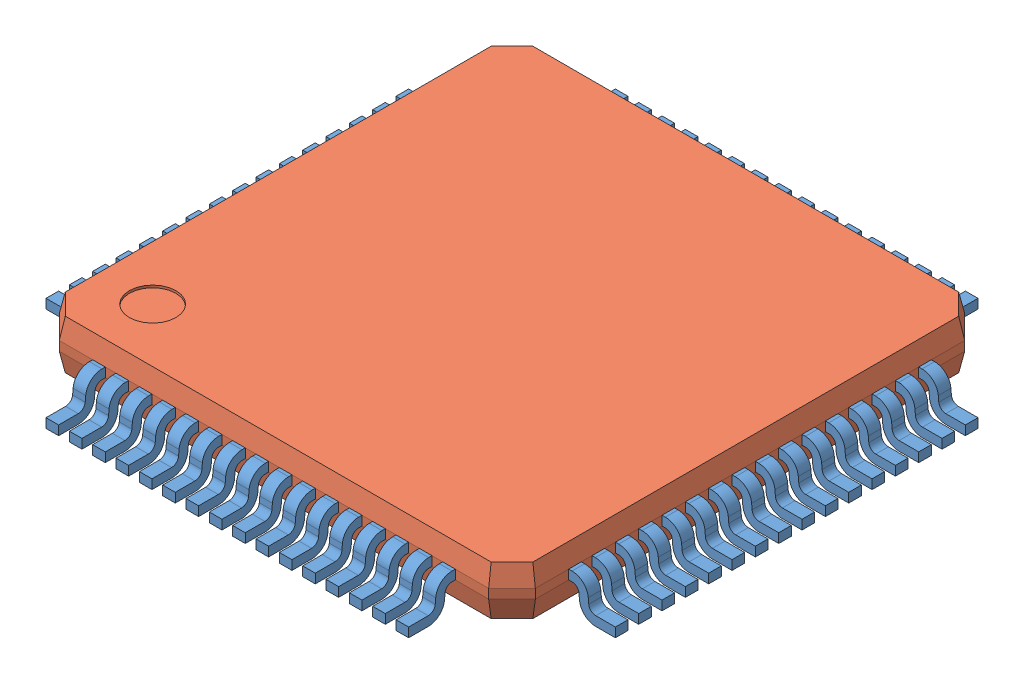
SolidWorks assembly User Library-TQFP64-2, configuration Default. Lengths in mm.
Overall size (12.2 1.2 12.2).
65 component instances, 2 part files, 0 mates.
Components (placement in the parent):
- User Library-TQFP64-2_Leg x0-27 y0-575 z1-0-1: User Library-TQFP64-2_Leg x0-27 y0-575 z1-0 [Default] at (-5.1 0 -1.25) x (0 0 1) z (-1 0 0) size (0.27 0.78 1)
- User Library-TQFP64-2_Leg x0-27 y0-575 z1-0-2: User Library-TQFP64-2_Leg x0-27 y0-575 z1-0 [Default] at (-2.75 0 -5.1001) x (-1 0 0) z (0 0 -1) size (0.27 0.78 1)
- User Library-TQFP64-2_Leg x0-27 y0-575 z1-0-3: User Library-TQFP64-2_Leg x0-27 y0-575 z1-0 [Default] at (-5.1 0 2.25) x (0 0 1) z (-1 0 0) size (0.27 0.78 1)
- User Library-TQFP64-2_Leg x0-27 y0-575 z1-0-4: User Library-TQFP64-2_Leg x0-27 y0-575 z1-0 [Default] at (5.1 0 -3.25) x (0 0 -1) z (1 0 0) size (0.27 0.78 1)
- User Library-TQFP64-2_Leg x0-27 y0-575 z1-0-5: User Library-TQFP64-2_Leg x0-27 y0-575 z1-0 [Default] at (-1.25 0 5.1001) size (0.27 0.78 1)
- User Library-TQFP64-2_Leg x0-27 y0-575 z1-0-6: User Library-TQFP64-2_Leg x0-27 y0-575 z1-0 [Default] at (2.75 0 5.1001) size (0.27 0.78 1)
- User Library-TQFP64-2_Leg x0-27 y0-575 z1-0-7: User Library-TQFP64-2_Leg x0-27 y0-575 z1-0 [Default] at (2.25 0 5.1001) size (0.27 0.78 1)
- User Library-TQFP64-2_Leg x0-27 y0-575 z1-0-8: User Library-TQFP64-2_Leg x0-27 y0-575 z1-0 [Default] at (5.1 0 -0.25) x (0 0 -1) z (1 0 0) size (0.27 0.78 1)
- User Library-TQFP64-2_Leg x0-27 y0-575 z1-0-9: User Library-TQFP64-2_Leg x0-27 y0-575 z1-0 [Default] at (-5.1 0 -0.75) x (0 0 1) z (-1 0 0) size (0.27 0.78 1)
- User Library-TQFP64-2_Leg x0-27 y0-575 z1-0-10: User Library-TQFP64-2_Leg x0-27 y0-575 z1-0 [Default] at (2.25 0 -5.1001) x (-1 0 0) z (0 0 -1) size (0.27 0.78 1)
- User Library-TQFP64-2_Leg x0-27 y0-575 z1-0-11: User Library-TQFP64-2_Leg x0-27 y0-575 z1-0 [Default] at (5.1 0 0.75) x (0 0 -1) z (1 0 0) size (0.27 0.78 1)
- User Library-TQFP64-2_Leg x0-27 y0-575 z1-0-12: User Library-TQFP64-2_Leg x0-27 y0-575 z1-0 [Default] at (-0.25 0 -5.1001) x (-1 0 0) z (0 0 -1) size (0.27 0.78 1)
- User Library-TQFP64-2_Leg x0-27 y0-575 z1-0-13: User Library-TQFP64-2_Leg x0-27 y0-575 z1-0 [Default] at (5.1 0 0.25) x (0 0 -1) z (1 0 0) size (0.27 0.78 1)
- User Library-TQFP64-2_Leg x0-27 y0-575 z1-0-14: User Library-TQFP64-2_Leg x0-27 y0-575 z1-0 [Default] at (1.75 0 5.1001) size (0.27 0.78 1)
- User Library-TQFP64-2_Leg x0-27 y0-575 z1-0-15: User Library-TQFP64-2_Leg x0-27 y0-575 z1-0 [Default] at (-1.25 0 -5.1001) x (-1 0 0) z (0 0 -1) size (0.27 0.78 1)
- User Library-TQFP64-2_Leg x0-27 y0-575 z1-0-16: User Library-TQFP64-2_Leg x0-27 y0-575 z1-0 [Default] at (-5.1 0 1.75) x (0 0 1) z (-1 0 0) size (0.27 0.78 1)
- User Library-TQFP64-2_Leg x0-27 y0-575 z1-0-17: User Library-TQFP64-2_Leg x0-27 y0-575 z1-0 [Default] at (3.25 0 5.1001) size (0.27 0.78 1)
- User Library-TQFP64-2_Leg x0-27 y0-575 z1-0-18: User Library-TQFP64-2_Leg x0-27 y0-575 z1-0 [Default] at (2.75 0 -5.1001) x (-1 0 0) z (0 0 -1) size (0.27 0.78 1)
- User Library-TQFP64-2_Leg x0-27 y0-575 z1-0-19: User Library-TQFP64-2_Leg x0-27 y0-575 z1-0 [Default] at (5.1 0 2.25) x (0 0 -1) z (1 0 0) size (0.27 0.78 1)
- User Library-TQFP64-2_Leg x0-27 y0-575 z1-0-20: User Library-TQFP64-2_Leg x0-27 y0-575 z1-0 [Default] at (-3.25 0 -5.1001) x (-1 0 0) z (0 0 -1) size (0.27 0.78 1)
- User Library-TQFP64-2_Leg x0-27 y0-575 z1-0-21: User Library-TQFP64-2_Leg x0-27 y0-575 z1-0 [Default] at (-3.75 0 5.1001) size (0.27 0.78 1)
- User Library-TQFP64-2_Leg x0-27 y0-575 z1-0-22: User Library-TQFP64-2_Leg x0-27 y0-575 z1-0 [Default] at (-3.25 0 5.1001) size (0.27 0.78 1)
- User Library-TQFP64-2_Leg x0-27 y0-575 z1-0-23: User Library-TQFP64-2_Leg x0-27 y0-575 z1-0 [Default] at (3.75 0 5.1001) size (0.27 0.78 1)
- User Library-TQFP64-2_Leg x0-27 y0-575 z1-0-24: User Library-TQFP64-2_Leg x0-27 y0-575 z1-0 [Default] at (-5.1 0 0.25) x (0 0 1) z (-1 0 0) size (0.27 0.78 1)
- User Library-TQFP64-2_Leg x0-27 y0-575 z1-0-25: User Library-TQFP64-2_Leg x0-27 y0-575 z1-0 [Default] at (5.1 0 3.25) x (0 0 -1) z (1 0 0) size (0.27 0.78 1)
- User Library-TQFP64-2_Leg x0-27 y0-575 z1-0-26: User Library-TQFP64-2_Leg x0-27 y0-575 z1-0 [Default] at (-5.1 0 0.75) x (0 0 1) z (-1 0 0) size (0.27 0.78 1)
- User Library-TQFP64-2_Leg x0-27 y0-575 z1-0-27: User Library-TQFP64-2_Leg x0-27 y0-575 z1-0 [Default] at (0.75 0 -5.1001) x (-1 0 0) z (0 0 -1) size (0.27 0.78 1)
- User Library-TQFP64-2_Leg x0-27 y0-575 z1-0-28: User Library-TQFP64-2_Leg x0-27 y0-575 z1-0 [Default] at (5.1 0 1.75) x (0 0 -1) z (1 0 0) size (0.27 0.78 1)
- User Library-TQFP64-2_Leg x0-27 y0-575 z1-0-29: User Library-TQFP64-2_Leg x0-27 y0-575 z1-0 [Default] at (-5.1 0 -3.75) x (0 0 1) z (-1 0 0) size (0.27 0.78 1)
- User Library-TQFP64-2_Leg x0-27 y0-575 z1-0-30: User Library-TQFP64-2_Leg x0-27 y0-575 z1-0 [Default] at (5.1 0 -0.75) x (0 0 -1) z (1 0 0) size (0.27 0.78 1)
- User Library-TQFP64-2_Leg x0-27 y0-575 z1-0-31: User Library-TQFP64-2_Leg x0-27 y0-575 z1-0 [Default] at (5.1 0 3.75) x (0 0 -1) z (1 0 0) size (0.27 0.78 1)
- User Library-TQFP64-2_Leg x0-27 y0-575 z1-0-32: User Library-TQFP64-2_Leg x0-27 y0-575 z1-0 [Default] at (-2.25 0 5.1001) size (0.27 0.78 1)
- User Library-TQFP64-2_Leg x0-27 y0-575 z1-0-33: User Library-TQFP64-2_Leg x0-27 y0-575 z1-0 [Default] at (-5.1 0 -3.25) x (0 0 1) z (-1 0 0) size (0.27 0.78 1)
- User Library-TQFP64-2_Leg x0-27 y0-575 z1-0-34: User Library-TQFP64-2_Leg x0-27 y0-575 z1-0 [Default] at (-5.1 0 2.75) x (0 0 1) z (-1 0 0) size (0.27 0.78 1)
- User Library-TQFP64-2_Leg x0-27 y0-575 z1-0-35: User Library-TQFP64-2_Leg x0-27 y0-575 z1-0 [Default] at (-5.1 0 3.75) x (0 0 1) z (-1 0 0) size (0.27 0.78 1)
- User Library-TQFP64-2_Leg x0-27 y0-575 z1-0-36: User Library-TQFP64-2_Leg x0-27 y0-575 z1-0 [Default] at (1.25 0 -5.1001) x (-1 0 0) z (0 0 -1) size (0.27 0.78 1)
- User Library-TQFP64-2_Leg x0-27 y0-575 z1-0-37: User Library-TQFP64-2_Leg x0-27 y0-575 z1-0 [Default] at (1.25 0 5.1001) size (0.27 0.78 1)
- User Library-TQFP64-2_Leg x0-27 y0-575 z1-0-38: User Library-TQFP64-2_Leg x0-27 y0-575 z1-0 [Default] at (5.1 0 1.25) x (0 0 -1) z (1 0 0) size (0.27 0.78 1)
- User Library-TQFP64-2_Leg x0-27 y0-575 z1-0-39: User Library-TQFP64-2_Leg x0-27 y0-575 z1-0 [Default] at (0.75 0 5.1001) size (0.27 0.78 1)
- User Library-TQFP64-2_Leg x0-27 y0-575 z1-0-40: User Library-TQFP64-2_Leg x0-27 y0-575 z1-0 [Default] at (3.25 0 -5.1001) x (-1 0 0) z (0 0 -1) size (0.27 0.78 1)
- User Library-TQFP64-2_Leg x0-27 y0-575 z1-0-41: User Library-TQFP64-2_Leg x0-27 y0-575 z1-0 [Default] at (-2.75 0 5.1001) size (0.27 0.78 1)
- User Library-TQFP64-2_Leg x0-27 y0-575 z1-0-42: User Library-TQFP64-2_Leg x0-27 y0-575 z1-0 [Default] at (3.75 0 -5.1001) x (-1 0 0) z (0 0 -1) size (0.27 0.78 1)
- User Library-TQFP64-2_Leg x0-27 y0-575 z1-0-43: User Library-TQFP64-2_Leg x0-27 y0-575 z1-0 [Default] at (1.75 0 -5.1001) x (-1 0 0) z (0 0 -1) size (0.27 0.78 1)
- User Library-TQFP64-2_Leg x0-27 y0-575 z1-0-44: User Library-TQFP64-2_Leg x0-27 y0-575 z1-0 [Default] at (-5.1 0 -2.75) x (0 0 1) z (-1 0 0) size (0.27 0.78 1)
- User Library-TQFP64-2_Leg x0-27 y0-575 z1-0-45: User Library-TQFP64-2_Leg x0-27 y0-575 z1-0 [Default] at (5.1 0 -2.25) x (0 0 -1) z (1 0 0) size (0.27 0.78 1)
- User Library-TQFP64-2_Leg x0-27 y0-575 z1-0-46: User Library-TQFP64-2_Leg x0-27 y0-575 z1-0 [Default] at (-2.25 0 -5.1001) x (-1 0 0) z (0 0 -1) size (0.27 0.78 1)
- User Library-TQFP64-2_Leg x0-27 y0-575 z1-0-47: User Library-TQFP64-2_Leg x0-27 y0-575 z1-0 [Default] at (-5.1 0 1.25) x (0 0 1) z (-1 0 0) size (0.27 0.78 1)
- User Library-TQFP64-2_Leg x0-27 y0-575 z1-0-48: User Library-TQFP64-2_Leg x0-27 y0-575 z1-0 [Default] at (5.1 0 -3.75) x (0 0 -1) z (1 0 0) size (0.27 0.78 1)
- User Library-TQFP64-2_Leg x0-27 y0-575 z1-0-49: User Library-TQFP64-2_Leg x0-27 y0-575 z1-0 [Default] at (0.25 0 -5.1001) x (-1 0 0) z (0 0 -1) size (0.27 0.78 1)
- User Library-TQFP64-2_Leg x0-27 y0-575 z1-0-50: User Library-TQFP64-2_Leg x0-27 y0-575 z1-0 [Default] at (-3.75 0 -5.1001) x (-1 0 0) z (0 0 -1) size (0.27 0.78 1)
- User Library-TQFP64-2_Leg x0-27 y0-575 z1-0-51: User Library-TQFP64-2_Leg x0-27 y0-575 z1-0 [Default] at (-5.1 0 -0.25) x (0 0 1) z (-1 0 0) size (0.27 0.78 1)
- User Library-TQFP64-2_Leg x0-27 y0-575 z1-0-52: User Library-TQFP64-2_Leg x0-27 y0-575 z1-0 [Default] at (-0.75 0 5.1001) size (0.27 0.78 1)
- User Library-TQFP64-2_Leg x0-27 y0-575 z1-0-53: User Library-TQFP64-2_Leg x0-27 y0-575 z1-0 [Default] at (5.1 0 -1.75) x (0 0 -1) z (1 0 0) size (0.27 0.78 1)
- User Library-TQFP64-2_Leg x0-27 y0-575 z1-0-54: User Library-TQFP64-2_Leg x0-27 y0-575 z1-0 [Default] at (-5.1 0 -2.25) x (0 0 1) z (-1 0 0) size (0.27 0.78 1)
- User Library-TQFP64-2_Leg x0-27 y0-575 z1-0-55: User Library-TQFP64-2_Leg x0-27 y0-575 z1-0 [Default] at (-0.75 0 -5.1001) x (-1 0 0) z (0 0 -1) size (0.27 0.78 1)
- User Library-TQFP64-2_Leg x0-27 y0-575 z1-0-56: User Library-TQFP64-2_Leg x0-27 y0-575 z1-0 [Default] at (-5.1 0 3.25) x (0 0 1) z (-1 0 0) size (0.27 0.78 1)
- User Library-TQFP64-2_Body x10-2 y10-2 z1-05-1: User Library-TQFP64-2_Body x10-2 y10-2 z1-05 [Default] at origin size (10.2 1.05 10.2)
- User Library-TQFP64-2_Leg x0-27 y0-575 z1-0-57: User Library-TQFP64-2_Leg x0-27 y0-575 z1-0 [Default] at (0.25 0 5.1001) size (0.27 0.78 1)
- User Library-TQFP64-2_Leg x0-27 y0-575 z1-0-58: User Library-TQFP64-2_Leg x0-27 y0-575 z1-0 [Default] at (5.1 0 2.75) x (0 0 -1) z (1 0 0) size (0.27 0.78 1)
- User Library-TQFP64-2_Leg x0-27 y0-575 z1-0-59: User Library-TQFP64-2_Leg x0-27 y0-575 z1-0 [Default] at (-1.75 0 -5.1001) x (-1 0 0) z (0 0 -1) size (0.27 0.78 1)
- User Library-TQFP64-2_Leg x0-27 y0-575 z1-0-60: User Library-TQFP64-2_Leg x0-27 y0-575 z1-0 [Default] at (-5.1 0 -1.75) x (0 0 1) z (-1 0 0) size (0.27 0.78 1)
- User Library-TQFP64-2_Leg x0-27 y0-575 z1-0-61: User Library-TQFP64-2_Leg x0-27 y0-575 z1-0 [Default] at (-0.25 0 5.1001) size (0.27 0.78 1)
- User Library-TQFP64-2_Leg x0-27 y0-575 z1-0-62: User Library-TQFP64-2_Leg x0-27 y0-575 z1-0 [Default] at (-1.75 0 5.1001) size (0.27 0.78 1)
- User Library-TQFP64-2_Leg x0-27 y0-575 z1-0-63: User Library-TQFP64-2_Leg x0-27 y0-575 z1-0 [Default] at (5.1 0 -2.75) x (0 0 -1) z (1 0 0) size (0.27 0.78 1)
- User Library-TQFP64-2_Leg x0-27 y0-575 z1-0-64: User Library-TQFP64-2_Leg x0-27 y0-575 z1-0 [Default] at (5.1 0 -1.25) x (0 0 -1) z (1 0 0) size (0.27 0.78 1)
